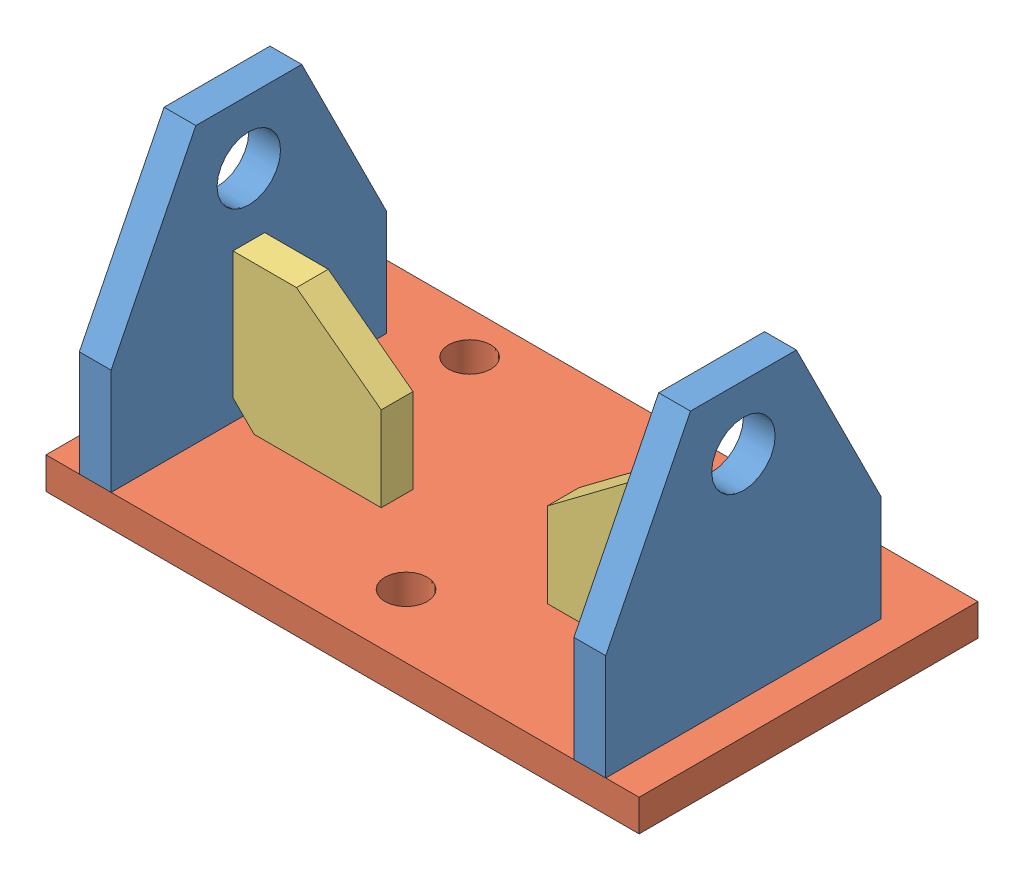
SolidWorks assembly Assem1, configuration Default. Lengths in mm.
Overall size (177.8 92.07 101.6).
5 component instances, 3 part files, 12 mates.
Components (placement in the parent):
- EndConnect-2: EndConnect [Default] at (165.4709 1.195 -38.3951) x (0 0 1) z (-1 0 0) size (82.55 82.55 9.53)
- RectBase-2: RectBase [Default] at (86.5709 -8.33 -47.9201) size (177.8 9.53 101.6)
- EndConnect-3: EndConnect [Default] at (17.1959 1.195 -38.3951) x (0 0 1) z (-1 0 0) size (82.55 82.55 9.53)
- Brace-4: Brace [Default] at (17.1959 1.195 -38.3976) x (1 0 0) z (0 -1 0) size (44.45 9.53 44.45)
- Brace-5: Brace [Default] at (155.9459 1.195 -38.3976) x (-1 0 0) z (0 -1 0) size (44.45 9.53 44.45)
Mates (geometry in assembly coordinates):
- Coincident5: coincident aligned: plane of EndConnect-2 through (155.9459 32.945 2.8799) normal (0 0 1); plane of RectBase-2 through (-2.3291 1.195 2.8799) normal (0 0 1)
- Coincident6: coincident anti-aligned: plane of EndConnect-2 through (155.9459 1.195 2.8799) normal (0 -1 0); plane of RectBase-2 through (-2.3291 1.195 2.8799) normal (0 1 0)
- Distance2: distance = 10 mm aligned: plane of EndConnect-2 through (165.4709 1.195 2.8799) normal (1 0 0); plane of RectBase-2 through (175.4709 1.195 -98.7201) normal (1 0 0)
- Coincident11: coincident aligned: plane of RectBase-2 through (-2.3291 1.195 2.8799) normal (0 0 1); plane of EndConnect-3 through (7.6709 32.945 2.8799) normal (0 0 1)
- Coincident12: coincident anti-aligned: plane of RectBase-2 through (-2.3291 1.195 2.8799) normal (0 1 0); plane of EndConnect-3 through (7.6709 1.195 2.8799) normal (0 -1 0)
- Distance4: distance = 10 mm aligned: plane of EndConnect-3 through (7.6709 1.195 2.8799) normal (-1 0 0); plane of RectBase-2 through (-2.3291 1.195 2.8799) normal (-1 0 0)
- Coincident16: coincident: plane of EndConnect-3 through (17.1959 1.195 2.8799) normal (1 0 0); plane of Brace-4 through (17.1959 1.195 -31.7822) normal (-1 0 0)
- Coincident17: coincident: plane of RectBase-2 through (-2.3291 1.195 2.8799) normal (0 1 0); plane of Brace-4 through (17.1959 1.195 -31.7822) normal (0 -1 0)
- Coincident18: coincident: plane of RectBase-2 through (-2.3291 1.195 2.8799) normal (0 1 0); plane of Brace-5 through (155.9459 1.195 -40.2489) normal (0 -1 0)
- Coincident19: coincident: plane of EndConnect-2 through (155.9459 1.195 2.8799) normal (-1 0 0); plane of Brace-5 through (155.9459 1.195 -40.2489) normal (1 0 0)
- Distance7: distance = 4.765 mm: plane of assembly; line of Brace-5 through (136.8959 45.645 -43.1601) axis (1 0 0)
- Distance9: distance = 4.765 mm: plane of assembly; line of Brace-4 through (36.2459 45.645 -43.1601) axis (-1 0 0)
